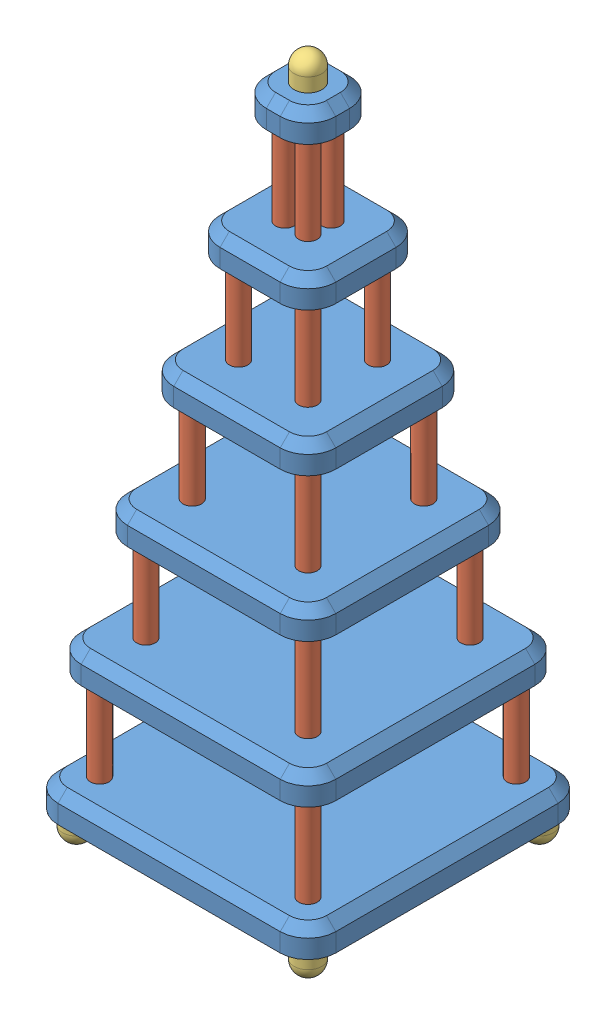
SolidWorks assembly Yucra_Fabrizio_E05, configuration Predeterminado. Lengths in mm.
Overall size (300 740 300).
31 component instances, 3 part files, 74 mates.
Components (placement in the parent):
- Yucra_Fabrizio_P57A-1: Yucra_Fabrizio_P57A [Configuracion 1] at (-66.8156 -10.8585 300) size (300 30 300)
- Yucra_Fabrizio_P57A-2: Yucra_Fabrizio_P57A [Configuracion 2] at (-66.8156 119.1415 300) size (275 30 275)
- Yucra_Fabrizio_P57A-3: Yucra_Fabrizio_P57A [Configuracion 3] at (-66.8156 249.1415 300) size (225 30 225)
- Yucra_Fabrizio_P57A-4: Yucra_Fabrizio_P57A [Configuracion 4] at (-66.8156 379.1415 300) size (175 30 175)
- Yucra_Fabrizio_P57A-5: Yucra_Fabrizio_P57A [Configuracion 5] at (-66.8156 509.1415 300) size (125 30 125)
- Yucra_Fabrizio_P57A-6: Yucra_Fabrizio_P57A [Configuracion 6] at (-66.8156 639.1415 300) size (75 30 75)
- Yucra_Fabrizio_P57B-1: Yucra_Fabrizio_P57B [Predeterminado] at (45.6844 69.1415 412.5) size (20 120 20)
- Yucra_Fabrizio_P57B-2: Yucra_Fabrizio_P57B [Predeterminado] at (45.6844 69.1415 187.5) size (20 120 20)
- Yucra_Fabrizio_P57B-3: Yucra_Fabrizio_P57B [Predeterminado] at (-179.3156 69.1415 412.5) size (20 120 20)
- Yucra_Fabrizio_P57B-4: Yucra_Fabrizio_P57B [Predeterminado] at (-179.3156 69.1415 187.5) size (20 120 20)
- Yucra_Fabrizio_P57B-5: Yucra_Fabrizio_P57B [Predeterminado] at (20.6844 199.1415 387.5) x (0.99984 0 -0.017868) z (0.017868 0 0.99984) size (20 120 20)
- Yucra_Fabrizio_P57B-6: Yucra_Fabrizio_P57B [Predeterminado] at (-54.3156 589.1415 287.5) x (0.972094 0 0.234592) z (-0.234592 0 0.972094) size (20 120 20)
- Yucra_Fabrizio_P57B-7: Yucra_Fabrizio_P57B [Predeterminado] at (20.6844 199.1415 212.5) x (0.939707 0 0.341982) z (-0.341982 0 0.939707) size (20 120 20)
- Yucra_Fabrizio_P57B-8: Yucra_Fabrizio_P57B [Predeterminado] at (-154.3156 199.1415 387.5) size (20 120 20)
- Yucra_Fabrizio_P57B-9: Yucra_Fabrizio_P57B [Predeterminado] at (-79.3156 589.1415 287.5) x (0.875884 0 -0.482523) z (0.482523 0 0.875884) size (20 120 20)
- Yucra_Fabrizio_P57B-10: Yucra_Fabrizio_P57B [Predeterminado] at (-129.3156 329.1415 237.5) x (-0.238641 0 0.971108) z (-0.971108 0 -0.238641) size (20 120 20)
- Yucra_Fabrizio_P57B-11: Yucra_Fabrizio_P57B [Predeterminado] at (-4.3156 329.1415 237.5) x (0.848096 0 -0.529842) z (0.529842 0 0.848096) size (20 120 20)
- Yucra_Fabrizio_P57B-12: Yucra_Fabrizio_P57B [Predeterminado] at (-4.3156 329.1415 362.5) x (-0.966006 0 -0.258519) z (0.258519 0 -0.966006) size (20 120 20)
- Yucra_Fabrizio_P57B-13: Yucra_Fabrizio_P57B [Predeterminado] at (-129.3156 329.1415 362.5) x (0.741254 0 -0.671225) z (0.671225 0 0.741254) size (20 120 20)
- Yucra_Fabrizio_P57B-14: Yucra_Fabrizio_P57B [Predeterminado] at (-29.3156 459.1415 337.5) x (0.910929 0 -0.412564) z (0.412564 0 0.910929) size (20 120 20)
- Yucra_Fabrizio_P57B-15: Yucra_Fabrizio_P57B [Predeterminado] at (-104.3156 459.1415 337.5) x (0.792403 0 -0.609998) z (0.609998 0 0.792403) size (20 120 20)
- Yucra_Fabrizio_P57B-16: Yucra_Fabrizio_P57B [Predeterminado] at (-29.3156 459.1415 262.5) size (20 120 20)
- Yucra_Fabrizio_P57B-17: Yucra_Fabrizio_P57B [Predeterminado] at (-54.3156 589.1415 312.5) x (0.983273 0 0.182135) z (-0.182135 0 0.983273) size (20 120 20)
- Yucra_Fabrizio_P57B-18: Yucra_Fabrizio_P57B [Predeterminado] at (-79.3156 589.1415 312.5) x (0.738394 0 0.67437) z (-0.67437 0 0.738394) size (20 120 20)
- Yucra_Fabrizio_P57B-19: Yucra_Fabrizio_P57B [Predeterminado] at (-104.3156 459.1415 262.5) size (20 120 20)
- Yucra_Fabrizio_P57B-20: Yucra_Fabrizio_P57B [Predeterminado] at (-154.3156 199.1415 212.5) size (20 120 20)
- Yucra_Fabrizio_P57C-1: Yucra_Fabrizio_P57C [Predeterminado] at (-191.8156 -40.8585 175) x (0.256278 0 -0.966603) z (0.966603 0 0.256278) size (30 40 30)
- Yucra_Fabrizio_P57C-2: Yucra_Fabrizio_P57C [Predeterminado] at (58.1844 -40.8585 175) x (0.600281 0 -0.799789) z (0.799789 0 0.600281) size (30 40 30)
- Yucra_Fabrizio_P57C-3: Yucra_Fabrizio_P57C [Predeterminado] at (58.1844 -40.8585 425) x (0.735926 0 -0.677062) z (0.677062 0 0.735926) size (30 40 30)
- Yucra_Fabrizio_P57C-4: Yucra_Fabrizio_P57C [Predeterminado] at (-191.8156 -40.8585 425) x (0.877802 0 -0.479024) z (0.479024 0 0.877802) size (30 40 30)
- Yucra_Fabrizio_P57C-5: Yucra_Fabrizio_P57C [Predeterminado] at (-66.8156 699.1415 300) x (-0.455015 0 -0.890484) z (-0.890484 0 0.455015) size (30 40 30)
Mates (geometry in assembly coordinates):
- Concéntrica1: concentric anti-aligned: cylinder of Yucra_Fabrizio_P57A-1 through (45.6844 9.1415 412.5) axis (0 1 0) radius 6; cylinder of Yucra_Fabrizio_P57B-1 through (45.6844 69.1415 412.5) axis (0 -1 0) radius 6
- Coincidente1: coincident anti-aligned: plane of Yucra_Fabrizio_P57A-1 through (-66.8156 19.1415 300) normal (0 1 0); plane of Yucra_Fabrizio_P57B-1 through (35.6844 19.1415 412.5) normal (0 -1 0)
- Concéntrica2: concentric anti-aligned: cylinder of Yucra_Fabrizio_P57A-1 through (-179.3156 9.1415 412.5) axis (0 1 0) radius 6; cylinder of Yucra_Fabrizio_P57B-3 through (-179.3156 69.1415 412.5) axis (0 -1 0) radius 6
- Coincidente2: coincident anti-aligned: plane of Yucra_Fabrizio_P57A-1 through (-66.8156 19.1415 300) normal (0 1 0); plane of Yucra_Fabrizio_P57B-3 through (-189.3156 19.1415 412.5) normal (0 -1 0)
- Concéntrica3: concentric anti-aligned: cylinder of Yucra_Fabrizio_P57A-1 through (45.6844 9.1415 187.5) axis (0 1 0) radius 6; cylinder of Yucra_Fabrizio_P57B-2 through (45.6844 69.1415 187.5) axis (0 -1 0) radius 6
- Coincidente3: coincident anti-aligned: plane of Yucra_Fabrizio_P57A-1 through (-66.8156 19.1415 300) normal (0 1 0); plane of Yucra_Fabrizio_P57B-2 through (35.6844 19.1415 187.5) normal (0 -1 0)
- Concéntrica4: concentric anti-aligned: cylinder of Yucra_Fabrizio_P57A-1 through (-179.3156 9.1415 187.5) axis (0 1 0) radius 6; cylinder of Yucra_Fabrizio_P57B-4 through (-179.3156 69.1415 187.5) axis (0 -1 0) radius 6
- Coincidente4: coincident anti-aligned: plane of Yucra_Fabrizio_P57A-1 through (-66.8156 19.1415 300) normal (0 1 0); plane of Yucra_Fabrizio_P57B-4 through (-189.3156 19.1415 187.5) normal (0 -1 0)
- Concéntrica5: concentric aligned: cylinder of Yucra_Fabrizio_P57A-2 through (45.6844 129.1415 187.5) axis (0 -1 0) radius 6; cylinder of Yucra_Fabrizio_P57B-2 through (45.6844 69.1415 187.5) axis (0 -1 0) radius 6
- Concéntrica6: concentric aligned: cylinder of Yucra_Fabrizio_P57A-2 through (-179.3156 129.1415 187.5) axis (0 -1 0) radius 6; cylinder of Yucra_Fabrizio_P57B-4 through (-179.3156 69.1415 187.5) axis (0 -1 0) radius 6
- Concéntrica7: concentric aligned: line of Yucra_Fabrizio_P57A-2 through (45.6844 129.1415 412.5) axis (0 -1 0); cylinder of Yucra_Fabrizio_P57B-1 through (45.6844 69.1415 412.5) axis (0 -1 0) radius 6
- Concéntrica8: concentric aligned: cylinder of Yucra_Fabrizio_P57A-2 through (-179.3156 129.1415 412.5) axis (0 -1 0) radius 6; cylinder of Yucra_Fabrizio_P57B-3 through (-179.3156 69.1415 412.5) axis (0 -1 0) radius 6
- Coincidente5: coincident anti-aligned: plane of Yucra_Fabrizio_P57A-2 through (-66.8156 119.1415 300) normal (0 -1 0); plane of Yucra_Fabrizio_P57B-2 through (39.6844 119.1415 187.5) normal (0 1 0)
- Concéntrica9: concentric anti-aligned: cylinder of Yucra_Fabrizio_P57A-2 through (20.6844 139.1415 387.5) axis (0 1 0) radius 6; cylinder of Yucra_Fabrizio_P57B-5 through (20.6844 199.1415 387.5) axis (0 -1 0) radius 6
- Coincidente6: coincident anti-aligned: plane of Yucra_Fabrizio_P57A-2 through (-66.8156 149.1415 300) normal (0 1 0); plane of Yucra_Fabrizio_P57B-5 through (10.686 149.1415 387.6787) normal (0 -1 0)
- Concéntrica10: concentric anti-aligned: cylinder of Yucra_Fabrizio_P57A-2 through (-154.3156 139.1415 387.5) axis (0 1 0) radius 6; cylinder of Yucra_Fabrizio_P57B-8 through (-154.3156 199.1415 387.5) axis (0 -1 0) radius 6
- Coincidente7: coincident anti-aligned: plane of Yucra_Fabrizio_P57A-2 through (-66.8156 149.1415 300) normal (0 1 0); plane of Yucra_Fabrizio_P57B-8 through (-164.3156 149.1415 387.5) normal (0 -1 0)
- Concéntrica11: concentric anti-aligned: cylinder of Yucra_Fabrizio_P57A-2 through (20.6844 139.1415 212.5) axis (0 1 0) radius 6; cylinder of Yucra_Fabrizio_P57B-7 through (20.6844 199.1415 212.5) axis (0 -1 0) radius 6
- Coincidente8: coincident anti-aligned: plane of Yucra_Fabrizio_P57A-2 through (-66.8156 149.1415 300) normal (0 1 0); plane of Yucra_Fabrizio_P57B-7 through (11.2873 149.1415 209.0802) normal (0 -1 0)
- Concéntrica12: concentric anti-aligned: cylinder of Yucra_Fabrizio_P57A-2 through (-154.3156 139.1415 212.5) axis (0 1 0) radius 6; cylinder of Yucra_Fabrizio_P57B-20 through (-154.3156 199.1415 212.5) axis (0 -1 0) radius 6
- Coincidente9: coincident anti-aligned: plane of Yucra_Fabrizio_P57A-2 through (-66.8156 149.1415 300) normal (0 1 0); plane of Yucra_Fabrizio_P57B-20 through (-164.3156 149.1415 212.5) normal (0 -1 0)
- Concéntrica13: concentric aligned: cylinder of Yucra_Fabrizio_P57A-3 through (-154.3156 259.1415 212.5) axis (0 -1 0) radius 6; cylinder of Yucra_Fabrizio_P57B-20 through (-154.3156 199.1415 212.5) axis (0 -1 0) radius 6
- Concéntrica14: concentric aligned: cylinder of Yucra_Fabrizio_P57A-3 through (-154.3156 259.1415 387.5) axis (0 -1 0) radius 6; cylinder of Yucra_Fabrizio_P57B-8 through (-154.3156 199.1415 387.5) axis (0 -1 0) radius 6
- Concéntrica15: concentric aligned: cylinder of Yucra_Fabrizio_P57A-3 through (20.6844 259.1415 212.5) axis (0 -1 0) radius 6; cylinder of Yucra_Fabrizio_P57B-7 through (20.6844 199.1415 212.5) axis (0 -1 0) radius 6
- Concéntrica16: concentric aligned: cylinder of Yucra_Fabrizio_P57A-3 through (20.6844 259.1415 387.5) axis (0 -1 0) radius 6; cylinder of Yucra_Fabrizio_P57B-5 through (20.6844 199.1415 387.5) axis (0 -1 0) radius 6
- Coincidente10: coincident anti-aligned: plane of Yucra_Fabrizio_P57A-3 through (-66.8156 249.1415 300) normal (0 -1 0); plane of Yucra_Fabrizio_P57B-7 through (15.0461 249.1415 210.4481) normal (0 1 0)
- Concéntrica17: concentric anti-aligned: cylinder of Yucra_Fabrizio_P57A-3 through (-4.3156 269.1415 362.5) axis (0 1 0) radius 6; cylinder of Yucra_Fabrizio_P57B-12 through (-4.3156 329.1415 362.5) axis (0 -1 0) radius 6
- Coincidente11: coincident anti-aligned: plane of Yucra_Fabrizio_P57A-3 through (-66.8156 279.1415 300) normal (0 1 0); plane of Yucra_Fabrizio_P57B-12 through (5.3444 279.1415 365.0852) normal (0 -1 0)
- Concéntrica18: concentric anti-aligned: cylinder of Yucra_Fabrizio_P57A-3 through (-129.3156 269.1415 362.5) axis (0 1 0) radius 6; cylinder of Yucra_Fabrizio_P57B-13 through (-129.3156 329.1415 362.5) axis (0 -1 0) radius 6
- Coincidente12: coincident anti-aligned: plane of Yucra_Fabrizio_P57A-3 through (-66.8156 279.1415 300) normal (0 1 0); plane of Yucra_Fabrizio_P57B-13 through (-136.7282 279.1415 369.2122) normal (0 -1 0)
- Concéntrica19: concentric anti-aligned: cylinder of Yucra_Fabrizio_P57A-3 through (-129.3156 269.1415 237.5) axis (0 1 0) radius 6; cylinder of Yucra_Fabrizio_P57B-10 through (-129.3156 329.1415 237.5) axis (0 -1 0) radius 6
- Coincidente13: coincident anti-aligned: plane of Yucra_Fabrizio_P57A-3 through (-66.8156 279.1415 300) normal (0 1 0); plane of Yucra_Fabrizio_P57B-10 through (-126.9292 279.1415 227.7889) normal (0 -1 0)
- Concéntrica20: concentric anti-aligned: cylinder of Yucra_Fabrizio_P57A-3 through (-4.3156 269.1415 237.5) axis (0 1 0) radius 6; cylinder of Yucra_Fabrizio_P57B-11 through (-4.3156 329.1415 237.5) axis (0 -1 0) radius 6
- Coincidente14: coincident anti-aligned: plane of Yucra_Fabrizio_P57A-3 through (-66.8156 279.1415 300) normal (0 1 0); plane of Yucra_Fabrizio_P57B-11 through (-12.7966 279.1415 242.7984) normal (0 -1 0)
- Concéntrica21: concentric aligned: cylinder of Yucra_Fabrizio_P57A-4 through (-4.3156 389.1415 362.5) axis (0 -1 0) radius 6; cylinder of Yucra_Fabrizio_P57B-12 through (-4.3156 329.1415 362.5) axis (0 -1 0) radius 6
- Concéntrica22: concentric aligned: cylinder of Yucra_Fabrizio_P57A-4 through (-4.3156 389.1415 237.5) axis (0 -1 0) radius 6; cylinder of Yucra_Fabrizio_P57B-11 through (-4.3156 329.1415 237.5) axis (0 -1 0) radius 6
- Concéntrica23: concentric aligned: cylinder of Yucra_Fabrizio_P57A-4 through (-129.3156 389.1415 237.5) axis (0 -1 0) radius 6; cylinder of Yucra_Fabrizio_P57B-10 through (-129.3156 329.1415 237.5) axis (0 -1 0) radius 6
- Concéntrica24: concentric aligned: cylinder of Yucra_Fabrizio_P57A-4 through (-129.3156 389.1415 362.5) axis (0 -1 0) radius 6; cylinder of Yucra_Fabrizio_P57B-13 through (-129.3156 329.1415 362.5) axis (0 -1 0) radius 6
- Coincidente15: coincident anti-aligned: plane of Yucra_Fabrizio_P57A-4 through (-66.8156 379.1415 300) normal (0 -1 0); plane of Yucra_Fabrizio_P57B-12 through (1.4804 379.1415 364.0511) normal (0 1 0)
- Concéntrica25: concentric anti-aligned: cylinder of Yucra_Fabrizio_P57A-4 through (-29.3156 399.1415 337.5) axis (0 1 0) radius 6; cylinder of Yucra_Fabrizio_P57B-14 through (-29.3156 459.1415 337.5) axis (0 -1 0) radius 6
- Coincidente16: coincident anti-aligned: plane of Yucra_Fabrizio_P57A-4 through (-66.8156 409.1415 300) normal (0 1 0); plane of Yucra_Fabrizio_P57B-14 through (-38.4249 409.1415 341.6256) normal (0 -1 0)
- Concéntrica26: concentric anti-aligned: line of Yucra_Fabrizio_P57A-4 through (-29.3156 399.1415 262.5) axis (0 1 0); cylinder of Yucra_Fabrizio_P57B-16 through (-29.3156 459.1415 262.5) axis (0 -1 0) radius 6
- Coincidente17: coincident anti-aligned: plane of Yucra_Fabrizio_P57A-4 through (-66.8156 409.1415 300) normal (0 1 0); plane of Yucra_Fabrizio_P57B-16 through (-39.3156 409.1415 262.5) normal (0 -1 0)
- Concéntrica27: concentric anti-aligned: cylinder of Yucra_Fabrizio_P57A-4 through (-104.3156 399.1415 337.5) axis (0 1 0) radius 6; cylinder of Yucra_Fabrizio_P57B-15 through (-104.3156 459.1415 337.5) axis (0 -1 0) radius 6
- Coincidente18: coincident anti-aligned: plane of Yucra_Fabrizio_P57A-4 through (-66.8156 409.1415 300) normal (0 1 0); plane of Yucra_Fabrizio_P57B-15 through (-112.2396 409.1415 343.6) normal (0 -1 0)
- Concéntrica28: concentric anti-aligned: line of Yucra_Fabrizio_P57A-4 through (-104.3156 399.1415 262.5) axis (0 1 0); cylinder of Yucra_Fabrizio_P57B-19 through (-104.3156 459.1415 262.5) axis (0 -1 0) radius 6
- Coincidente19: coincident anti-aligned: plane of Yucra_Fabrizio_P57A-4 through (-66.8156 409.1415 300) normal (0 1 0); plane of Yucra_Fabrizio_P57B-19 through (-114.3156 409.1415 262.5) normal (0 -1 0)
- Concéntrica29: concentric aligned: cylinder of Yucra_Fabrizio_P57A-5 through (-29.3156 519.1415 337.5) axis (0 -1 0) radius 6; cylinder of Yucra_Fabrizio_P57B-14 through (-29.3156 459.1415 337.5) axis (0 -1 0) radius 6
- Concéntrica30: concentric aligned: cylinder of Yucra_Fabrizio_P57A-5 through (-29.3156 519.1415 262.5) axis (0 -1 0) radius 6; cylinder of Yucra_Fabrizio_P57B-16 through (-29.3156 459.1415 262.5) axis (0 -1 0) radius 6
- Concéntrica31: concentric aligned: cylinder of Yucra_Fabrizio_P57A-5 through (-104.3156 519.1415 262.5) axis (0 -1 0) radius 6; cylinder of Yucra_Fabrizio_P57B-19 through (-104.3156 459.1415 262.5) axis (0 -1 0) radius 6
- Coincidente20: coincident anti-aligned: plane of Yucra_Fabrizio_P57A-5 through (-66.8156 509.1415 300) normal (0 -1 0); plane of Yucra_Fabrizio_P57B-16 through (-35.3156 509.1415 262.5) normal (0 1 0)
- Concéntrica32: concentric anti-aligned: cylinder of Yucra_Fabrizio_P57A-5 through (-54.3156 529.1415 312.5) axis (0 1 0) radius 6; cylinder of Yucra_Fabrizio_P57B-17 through (-54.3156 589.1415 312.5) axis (0 -1 0) radius 6
- Concéntrica33: concentric anti-aligned: cylinder of Yucra_Fabrizio_P57A-5 through (-79.3156 529.1415 312.5) axis (0 1 0) radius 6; cylinder of Yucra_Fabrizio_P57B-18 through (-79.3156 589.1415 312.5) axis (0 -1 0) radius 6
- Concéntrica34: concentric anti-aligned: cylinder of Yucra_Fabrizio_P57A-5 through (-79.3156 529.1415 287.5) axis (0 1 0) radius 6; cylinder of Yucra_Fabrizio_P57B-9 through (-79.3156 589.1415 287.5) axis (0 -1 0) radius 6
- Concéntrica35: concentric anti-aligned: cylinder of Yucra_Fabrizio_P57A-5 through (-54.3156 529.1415 287.5) axis (0 1 0) radius 6; cylinder of Yucra_Fabrizio_P57B-6 through (-54.3156 589.1415 287.5) axis (0 -1 0) radius 6
- Coincidente21: coincident anti-aligned: plane of Yucra_Fabrizio_P57A-5 through (-66.8156 539.1415 300) normal (0 1 0); plane of Yucra_Fabrizio_P57B-6 through (-64.0366 539.1415 285.1541) normal (0 -1 0)
- Coincidente22: coincident anti-aligned: plane of Yucra_Fabrizio_P57A-5 through (-66.8156 539.1415 300) normal (0 1 0); plane of Yucra_Fabrizio_P57B-17 through (-64.1484 539.1415 310.6786) normal (0 -1 0)
- Coincidente23: coincident anti-aligned: plane of Yucra_Fabrizio_P57A-5 through (-66.8156 539.1415 300) normal (0 1 0); plane of Yucra_Fabrizio_P57B-18 through (-86.6996 539.1415 305.7563) normal (0 -1 0)
- Coincidente24: coincident anti-aligned: plane of Yucra_Fabrizio_P57A-5 through (-66.8156 539.1415 300) normal (0 1 0); plane of Yucra_Fabrizio_P57B-9 through (-88.0745 539.1415 292.3252) normal (0 -1 0)
- Concéntrica36: concentric aligned: cylinder of Yucra_Fabrizio_P57A-6 through (-79.3156 649.1415 312.5) axis (0 -1 0) radius 6; cylinder of Yucra_Fabrizio_P57B-18 through (-79.3156 589.1415 312.5) axis (0 -1 0) radius 6
- Concéntrica37: concentric aligned: cylinder of Yucra_Fabrizio_P57A-6 through (-79.3156 649.1415 287.5) axis (0 -1 0) radius 6; cylinder of Yucra_Fabrizio_P57B-9 through (-79.3156 589.1415 287.5) axis (0 -1 0) radius 6
- Concéntrica38: concentric aligned: cylinder of Yucra_Fabrizio_P57A-6 through (-54.3156 649.1415 287.5) axis (0 -1 0) radius 6; cylinder of Yucra_Fabrizio_P57B-6 through (-54.3156 589.1415 287.5) axis (0 -1 0) radius 6
- Concéntrica39: concentric aligned: cylinder of Yucra_Fabrizio_P57A-6 through (-54.3156 649.1415 312.5) axis (0 -1 0) radius 6; cylinder of Yucra_Fabrizio_P57B-17 through (-54.3156 589.1415 312.5) axis (0 -1 0) radius 6
- Coincidente25: coincident anti-aligned: plane of Yucra_Fabrizio_P57A-6 through (-66.8156 639.1415 300) normal (0 -1 0); plane of Yucra_Fabrizio_P57B-18 through (-83.746 639.1415 308.4538) normal (0 1 0)
- Concéntrica40: concentric aligned: cylinder of Yucra_Fabrizio_P57A-6 through (-66.8156 659.1415 300) axis (0 1 0) radius 6; cylinder of Yucra_Fabrizio_P57C-5 through (-66.8156 699.1415 300) axis (0 1 0) radius 6
- Coincidente26: coincident anti-aligned: plane of Yucra_Fabrizio_P57A-6 through (-66.8156 669.1415 300) normal (0 1 0); plane of Yucra_Fabrizio_P57C-5 through (-69.5457 669.1415 294.6571) normal (0 -1 0)
- Concéntrica41: concentric aligned: cylinder of Yucra_Fabrizio_P57A-1 through (-191.8156 -0.8585 425) axis (0 -1 0) radius 6; cylinder of Yucra_Fabrizio_P57C-4 through (-191.8156 -40.8585 425) axis (0 -1 0) radius 6
- Coincidente27: coincident anti-aligned: plane of Yucra_Fabrizio_P57A-1 through (-66.8156 -10.8585 300) normal (0 -1 0); plane of Yucra_Fabrizio_P57C-4 through (-186.5488 -10.8585 422.1259) normal (0 1 0)
- Concéntrica42: concentric aligned: cylinder of Yucra_Fabrizio_P57A-1 through (-191.8156 -0.8585 175) axis (0 -1 0) radius 6; cylinder of Yucra_Fabrizio_P57C-1 through (-191.8156 -40.8585 175) axis (0 -1 0) radius 6
- Coincidente28: coincident anti-aligned: plane of Yucra_Fabrizio_P57A-1 through (-66.8156 -10.8585 300) normal (0 -1 0); plane of Yucra_Fabrizio_P57C-1 through (-190.278 -10.8585 169.2004) normal (0 1 0)
- Concéntrica43: concentric aligned: line of Yucra_Fabrizio_P57A-1 through (58.1844 -0.8585 425) axis (0 -1 0); cylinder of Yucra_Fabrizio_P57C-3 through (58.1844 -40.8585 425) axis (0 -1 0) radius 6
- Coincidente29: coincident anti-aligned: plane of Yucra_Fabrizio_P57A-1 through (-66.8156 -10.8585 300) normal (0 -1 0); plane of Yucra_Fabrizio_P57C-3 through (62.5999 -10.8585 420.9376) normal (0 1 0)
- Concéntrica44: concentric aligned: cylinder of Yucra_Fabrizio_P57A-1 through (58.1844 -0.8585 175) axis (0 -1 0) radius 6; cylinder of Yucra_Fabrizio_P57C-2 through (58.1844 -40.8585 175) axis (0 -1 0) radius 6
- Coincidente31: coincident anti-aligned: plane of Yucra_Fabrizio_P57A-1 through (-66.8156 -10.8585 300) normal (0 -1 0); plane of Yucra_Fabrizio_P57C-2 through (61.7861 -10.8585 170.2013) normal (0 1 0)
